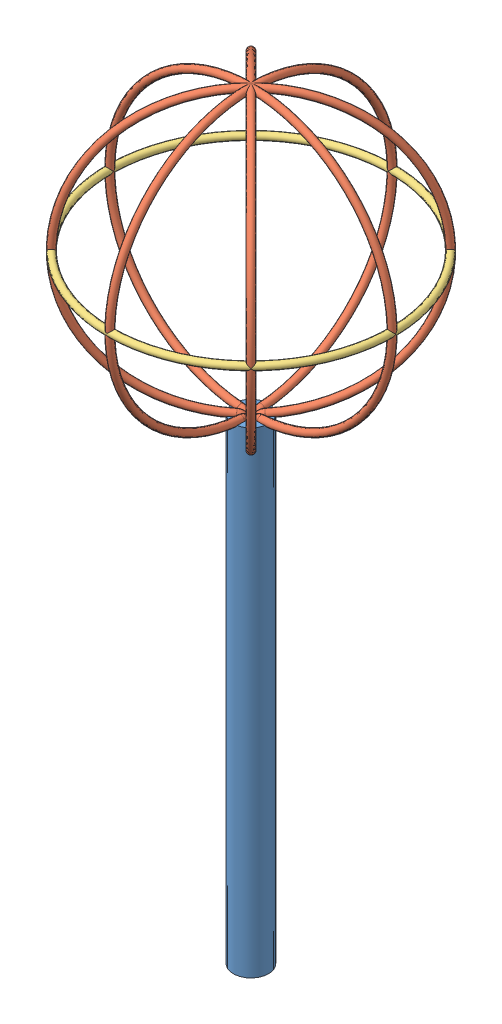
SolidWorks assembly Cathode Assembly, configuration Default. Lengths in mm.
Overall size (52.1 137.16 52.1).
7 component instances, 3 part files, 6 mates.
Components (placement in the parent):
- Cathode Rod-1: Cathode Rod [Default] at (0 -111.1164 0) x (-0.080916 0 -0.996721) z (0 1 0) size (6.35 6.35 85.72)
- Cathode-1: Cathode [Default] at (-23.1416 -39.3287 -39.2327) size (52.1 57.79 52.1)
  - Cathode Longitude-1: Cathode Longitude [Default] at (23.1416 39.3287 39.2327) size (52.1 57.79 1.3)
  - Cathode Longitude-2: Cathode Longitude [Default] at (23.1416 39.3287 39.2327) x (0 0 1) z (-1 0 0) size (52.1 57.79 1.3)
  - Cathode Longitude-3: Cathode Longitude [Default] at (23.1416 39.3287 39.2327) x (0.707107 0 0.707107) z (-0.707107 0 0.707107) size (52.1 57.79 1.3)
  - Cathode Longitude-4: Cathode Longitude [Default] at (23.1416 39.3287 39.2327) x (-0.707107 0 0.707107) z (-0.707107 0 -0.707107) size (52.1 57.79 1.3)
  - Cathode Equator-1: Cathode Equator [Default] at (23.1416 39.3287 39.2327) size (52.1 1.3 52.1)
Mates (geometry in assembly coordinates):
- Concentric2: concentric anti-aligned: cylinder of Cathode Rod-1 through (0 -25.3914 0) axis (0 -1 0) radius 3.175; line of Cathode-1/Cathode Longitude-3 through (63.568 0 -34.6309) axis (0 0 1)
- Coincident2: coincident anti-aligned: plane of Cathode Rod-1 through (0 -31.7414 0) normal (0 1 0); plane of Cathode-1/Cathode Longitude-2 through (0 -31.7414 0.6604) normal (0 -1 0)
- Coincident3: coincident: line of ? through (63.568 0 -34.6309) axis (0 0 1)
- Coincident4: coincident: plane of ? through (0 0 0) normal (0 1 0)
- Coincident5: coincident: line of ? through (63.568 0 -34.6309) axis (0 0 1)
- Coincident6: coincident aligned: plane of Cathode-1/Cathode Longitude-1 through (0 0 0) normal (0 0 1); plane of assembly through (0 0 0) normal (0 0 1)
